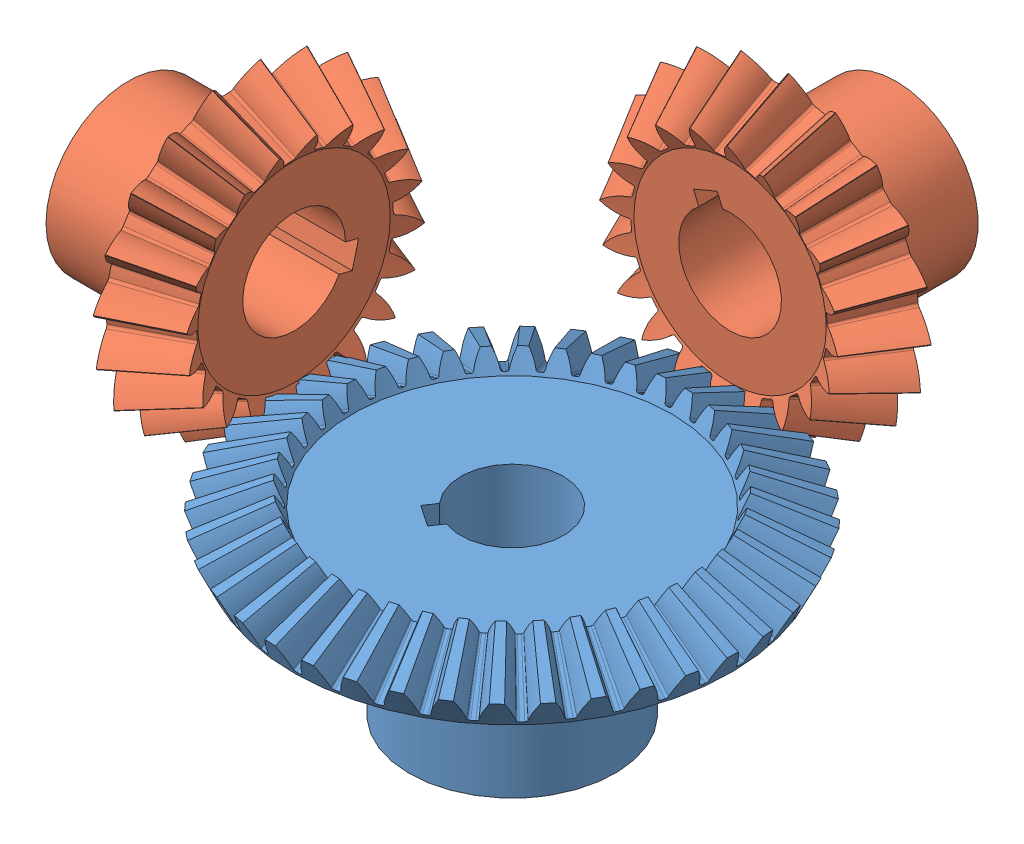
SolidWorks assembly Assem3, configuration Default. Lengths in mm.
Overall size (130.73 87.78 130.73).
3 component instances, 2 part files, 8 mates.
Components (placement in the parent):
- straight bevel gear_ai-3: straight bevel gear_ai [Inch - Straight bevel gear 12DP 40GT 19PT 20PA 0.5FW ---40O1.5H2.0MD0.75S1] x (0 1 0) z (0.827432 0 0.561567) size (37.56 85.83 85.83)
- straight bevel pinion_ai-1: straight bevel pinion_ai [Inch - Straight bevel pinion 10DP20PT 40GT 20PA 0.5FW ---20O1.2H2.8MD0.75S1] at (-52.0254 23.8562 0) x (1 0 0) z (0 0.968776 -0.247937) size (33.59 56.42 56.42)
- straight bevel pinion_ai-2: straight bevel pinion_ai [Inch - Straight bevel pinion 10DP20PT 40GT 20PA 0.5FW ---20O1.2H2.8MD0.75S1] at (0 23.8562 -52.0254) x (0 0 1) z (-0.920781 -0.390079 0) size (33.59 56.42 56.42)
Mates (geometry in assembly coordinates):
- Coincident1: coincident anti-aligned: plane of straight bevel gear_ai-3 through (0 0 0) normal (0 -1 0)
- Concentric1: concentric: cylinder of straight bevel gear_ai-3 through (0 50.8001 0) axis (0 -1 0) radius 9.525
- Coincident4: coincident: point of straight bevel gear_ai-3; point of straight bevel pinion_ai-1
- Perpendicular1: perpendicular: line of straight bevel gear_ai-3 through (0 -10 0) axis (0 1 0); line of straight bevel pinion_ai-1 through (-62.0254 23.8562 0) axis (1 0 0)
- Coincident6: coincident: line of straight bevel pinion_ai-1 through (-62.0254 23.8562 0) axis (1 0 0)
- Coincident7: coincident: point of straight bevel gear_ai-3; point of straight bevel pinion_ai-2
- Perpendicular2: perpendicular: line of straight bevel gear_ai-3 through (0 -10 0) axis (0 1 0); line of straight bevel pinion_ai-2 through (0 23.8562 -62.0254) axis (0 0 1)
- Coincident10: coincident: line of straight bevel pinion_ai-2 through (0 23.8562 -62.0254) axis (0 0 1)
